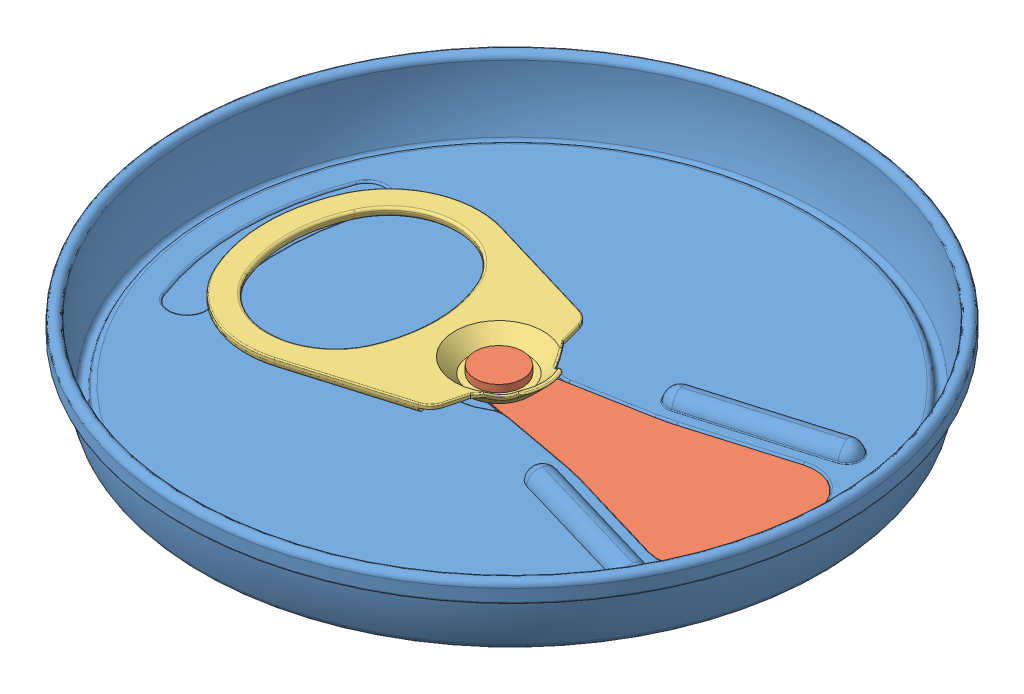
SolidWorks assembly Coke Can Assembly, configuration Default. Lengths in mm.
Overall size (55.06 6.11 55.06).
3 component instances, 3 part files, 4 mates.
Components (placement in the parent):
- Cap-1: Cap [Default] at (2.0859 2.2946 -2.1483) size (55.06 6.11 55.06)
- Opener Part 1-1: Opener Part 1 [Default] at (2.0859 2.2946 -2.1483) size (25.62 1.11 13.08)
- Opener Part 2-1: Opener Part 2 [Default] at (2.0859 2.2946 -2.1483) size (23.69 1.61 20.98)
Mates (geometry in assembly coordinates):
- Coincident3: coincident aligned: plane of Opener Part 1-1 through (62.8002 115.7756 71.8963) normal (0 -1 0); plane of Cap-1 through (88.419 115.7756 71.8963) normal (0 -1 0)
- Concentric1: concentric anti-aligned: circle of Cap-1; circle of Opener Part 1-1
- Coincident4: coincident anti-aligned: plane of Opener Part 1-1 through (65.7612 115.9556 76.3896) normal (0 1 0); plane of Opener Part 2-1 through (62.8002 115.9556 71.8963) normal (0 -1 0)
- Concentric2: concentric aligned: cylinder of Opener Part 1-1 through (62.8002 500002.2946 71.8963) axis (0 -1 0) radius 1.4; cylinder of Opener Part 2-1 through (62.8002 121.9424 71.8963) axis (0 -1 0) radius 1.4
